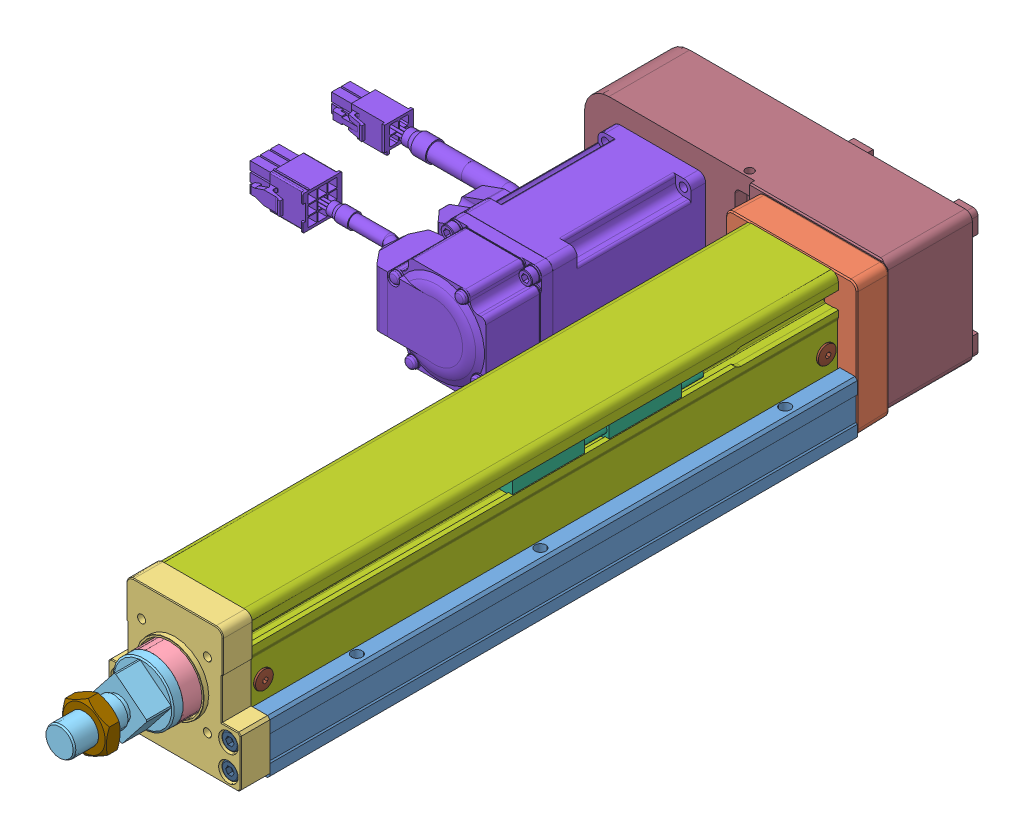
SolidWorks assembly CFY5-BL-100W, configuration Default. Lengths in mm.
Overall size (197.79 55.75 350).
25 component instances, 14 part files, 57 mates.
Components (placement in the parent):
- 底座GY5^CFY5-BL-100W-1: 底座GY5^CFY5-BL-100W [默认] at (172.2343 500.0265 205.4117) x (1 0 0) z (0 -1 0) size (54 240 25) (virtual)
- 丝杆座板GY5^CFY5-BL-100W-1: 丝杆座板GY5^CFY5-BL-100W [默认] at (172.2343 515.5765 191.9117) size (54.09 55.09 28) (virtual)
- 轴承座Y5^CFY5-BL-100W-1: 轴承座Y5^CFY5-BL-100W [Default] at (172.2343 516.7765 445.4117) size (54 54 22) (virtual)
- 推杆Y5^CFY5-BL-100W-1: 推杆Y5^CFY5-BL-100W [Default] at (172.2343 516.7765 316.4117) x (-0.030388 -0.999538 0) z (-0.999538 0.030388 0) size (25 150 25) (virtual)
- 螺纹连接头Y5^CFY5-BL-100W-1: 螺纹连接头Y5^CFY5-BL-100W [Default] at (172.2343 516.7765 470.4117) x (-0.620248 -0.784406 0) z (0 0 -1) size (25 25 47) (virtual)
- 磁性感应开关^CFY5-BL-100W-2: 磁性感应开关^CFY5-BL-100W [默认] at (191.3174 533.4018 308.9117) x (1 0 0) z (0 0 -1) size (5 6.3 39.5) (virtual)
- 上盖Y5^CFY5-BL-100W-1: 上盖Y5^CFY5-BL-100W [Default] at (153.6454 513.9765 205.4117) size (38.57 34 240) (virtual)
- 松下100W电机MSMF012L1U2^CFY5-BL-100W-1: 松下100W电机MSMF012L1U2^CFY5-BL-100W [默认] at (103.2343 516.7765 190.4117) x (0 0 -1) z (0 1 0) size (118.87 120.84 38.2) (virtual)
- 磁性感应开关^CFY5-BL-100W-3: 磁性感应开关^CFY5-BL-100W [默认] at (191.3174 533.4018 269.4117) x (1 0 0) z (0 0 -1) size (5 6.3 39.5) (virtual)
- 磁性感应开关^CFY5-BL-100W-4: 磁性感应开关^CFY5-BL-100W [默认] at (153.1454 533.4018 385.4117) x (-1 0 0) z (0 0 -1) size (5 6.3 39.5) (virtual)
- 六角薄螺母M12×1.25^CFY5-BL-100W-1: 六角薄螺母M12×1.25^CFY5-BL-100W [默认] at (172.2343 516.7765 494.4117) x (0.828588 -0.559859 0) z (0 0 1) size (20.78 18 6) (virtual)
- hexagon socket head cap screws gb-6: hexagon socket head cap screws gb [GB_FASTENER_SCREWS_HSHCS M4X12-N] at (194.2343 504.2765 456.8117) x (0 0 -1) z (1 0 0) size (16 7 7)
- hexagon socket head cap screws gb-7: hexagon socket head cap screws gb [GB_FASTENER_SCREWS_HSHCS M4X12-N] at (194.2343 493.7765 456.8117) x (0 0 -1) z (1 0 0) size (16 7 7)
- hexagon socket head cap screws gb-8: hexagon socket head cap screws gb [GB_FASTENER_SCREWS_HSHCS M4X12-N] at (150.2343 493.7765 456.8117) x (0 0 -1) z (1 0 0) size (16 7 7)
- hexagon socket head cap screws gb-9: hexagon socket head cap screws gb [GB_FASTENER_SCREWS_HSHCS M4X12-N] at (150.2343 504.2765 456.8117) x (0 0 -1) z (1 0 0) size (16 7 7)
- 内六角螺丝M3X5^CFY5-BL-100W-1: 内六角螺丝M3X5^CFY5-BL-100W [默认] at (186.1785 516.7765 210.4117) x (0 -1 0) z (0 0 1) size (7.5 6.19 7.5) (virtual)
- 内六角螺丝M3X5^CFY5-BL-100W-2: 内六角螺丝M3X5^CFY5-BL-100W [默认] at (186.1785 516.7765 440.4117) x (0 -0.21215 -0.977237) z (0 -0.977237 0.21215) size (7.5 6.19 7.5) (virtual)
- 内六角螺丝M3X5^CFY5-BL-100W-3: 内六角螺丝M3X5^CFY5-BL-100W [默认] at (158.2843 516.7765 440.4117) x (0 0.554408 0.832245) z (0 -0.832245 0.554408) size (7.5 6.19 7.5) (virtual)
- 内六角螺丝M3X5^CFY5-BL-100W-4: 内六角螺丝M3X5^CFY5-BL-100W [默认] at (158.2843 516.7765 210.4117) x (0 -0.497668 -0.867368) z (0 0.867368 -0.497668) size (7.5 6.19 7.5) (virtual)
- 304电机盖板Y5^CFY5-BL-100W-1: 304电机盖板Y5^CFY5-BL-100W [默认] at (135.4843 516.7765 157.4117) x (0 1 0) z (-1 0 0) size (51.5 1 123.5) (virtual)
- 电机板Y5-BLRM-P38^CFY5-BL-100W-1: 电机板Y5-BLRM-P38^CFY5-BL-100W [默认] at (124.0343 517.5265 205.4117) x (0 0 1) z (0 1 0) size (38 125.5 53.5) (virtual)
- hexagon socket button head screws gb-7: hexagon socket button head screws gb [GB_SOCKET_TYPE7 M3X6-N] at (79.2343 529.2765 154.7617) x (0 0 1) z (-1 0 0) size (7.65 5.7 5.7)
- hexagon socket button head screws gb-8: hexagon socket button head screws gb [GB_SOCKET_TYPE7 M3X6-N] at (79.2343 504.2765 154.7617) x (0 0 1) z (-1 0 0) size (7.65 5.7 5.7)
- hexagon socket button head screws gb-9: hexagon socket button head screws gb [GB_SOCKET_TYPE7 M3X6-N] at (192.2343 529.2765 154.7617) x (0 0 1) z (-1 0 0) size (7.65 5.7 5.7)
- hexagon socket button head screws gb-10: hexagon socket button head screws gb [GB_SOCKET_TYPE7 M3X6-N] at (192.2343 504.2765 154.7617) x (0 0 1) z (-1 0 0) size (7.65 5.7 5.7)
Mates (geometry in assembly coordinates):
- 同心129: concentric: cylinder of 推杆Y5^CFY5-BL-100W-1 through (172.2343 516.7765 466.4117) axis (0 0 -1) radius 8.5; cylinder of 螺纹连接头Y5^CFY5-BL-100W-1 through (172.2343 516.7765 457.4117) axis (0 0 1) radius 10
- 重合133: coincident: plane of 推杆Y5^CFY5-BL-100W-1 through (172.2343 516.7765 466.4117) normal (0 0 1); plane of 螺纹连接头Y5^CFY5-BL-100W-1 through (172.2343 516.7765 466.4117) normal (0 0 -1)
- 同心133: concentric: cylinder of 底座GY5^CFY5-BL-100W-1 through (194.2343 493.7765 445.4117) axis (0 0 1) radius 1.65; cylinder of 轴承座Y5^CFY5-BL-100W-1 through (194.2343 493.7765 457.4117) axis (0 0 1) radius 2.25
- 重合134: coincident: plane of 底座GY5^CFY5-BL-100W-1 through (167.2343 487.8265 445.4117) normal (0 0 1); plane of 轴承座Y5^CFY5-BL-100W-1 through (172.2343 516.7765 445.4117) normal (0 0 -1)
- 同心136: concentric: cylinder of 底座GY5^CFY5-BL-100W-1 through (150.2343 504.2765 445.4117) axis (0 0 1) radius 1.65; cylinder of 轴承座Y5^CFY5-BL-100W-1 through (150.2343 504.2765 457.4117) axis (0 0 1) radius 2.25
- 重合143: coincident: plane of 底座GY5^CFY5-BL-100W-1 through (167.2343 487.8265 445.4117) normal (0 0 1); plane of 上盖Y5^CFY5-BL-100W-1 through (158.1567 536.5769 445.4117) normal (0 0 1)
- 重合144: coincident: plane of 底座GY5^CFY5-BL-100W-1 through (190.0843 508.7765 445.4117) normal (0 1 0); plane of 上盖Y5^CFY5-BL-100W-1 through (191.1785 508.7765 445.4117) normal (0 -1 0)
- 宽度31: width: plane of 磁性感应开关^CFY5-BL-100W-2 through (186.3174 530.2518 338.4117) normal (0 -1 0); plane of 磁性感应开关^CFY5-BL-100W-2 through (186.3174 536.5518 308.9117) normal (0 1 0); plane of 上盖Y5^CFY5-BL-100W-1 through (158.1567 529.7267 445.4117) normal (0 1 0); plane of 上盖Y5^CFY5-BL-100W-1 through (154.9454 537.0769 445.4117) normal (0 -1 0)
- 重合1579: coincident: plane of 底座GY5^CFY5-BL-100W-1 through (154.3843 512.7765 445.4117) normal (-1 0 0); plane of 上盖Y5^CFY5-BL-100W-1 through (154.3843 527.7267 445.4117) normal (1 0 0)
- 重合1583: coincident: line of 磁性感应开关^CFY5-BL-100W-2 through (186.3174 530.2518 338.4117) axis (0 0 -1); plane of 磁性感应开关^CFY5-BL-100W-3 through (186.3174 533.4018 269.4117) normal (-1 0 0)
- 重合1586: coincident: plane of 磁性感应开关^CFY5-BL-100W-2 through (186.3174 530.2518 338.4117) normal (0 -1 0); plane of 磁性感应开关^CFY5-BL-100W-3 through (186.3174 530.2518 298.9117) normal (0 -1 0)
- 重合1603: coincident: plane of 磁性感应开关^CFY5-BL-100W-2 through (188.8174 533.4018 298.9117) normal (0 0 -1); plane of 磁性感应开关^CFY5-BL-100W-3 through (186.3174 536.5518 298.9117) normal (0 0 1)
- 距离9: distance = 30.5 mm: plane of 磁性感应开关^CFY5-BL-100W-4 through (158.1454 530.2518 414.9117) normal (0 0 1); plane of 轴承座Y5^CFY5-BL-100W-1 through (172.2343 516.7765 445.4117) normal (0 0 -1)
- 同心1661: concentric: cylinder of 底座GY5^CFY5-BL-100W-1 through (194.3343 506.7765 205.4117) axis (0 0 -1) radius 1.65; cylinder of 丝杆座板GY5^CFY5-BL-100W-1 through (194.3343 506.7765 192.4117) axis (0 0 -1) radius 4
- 同心1662: concentric: cylinder of 底座GY5^CFY5-BL-100W-1 through (150.1343 506.7765 205.4117) axis (0 0 -1) radius 1.65; cylinder of 丝杆座板GY5^CFY5-BL-100W-1 through (150.1343 506.7765 192.4117) axis (0 0 -1) radius 2.4
- 重合1605: coincident: plane of 底座GY5^CFY5-BL-100W-1 through (167.2343 487.8265 205.4117) normal (0 0 -1); plane of 丝杆座板GY5^CFY5-BL-100W-1 through (172.2343 515.5765 205.4117) normal (0 0 1)
- 距离11: distance = 64 mm: plane of 磁性感应开关^CFY5-BL-100W-3 through (186.3174 530.2518 269.4117) normal (0 0 -1); plane of 丝杆座板GY5^CFY5-BL-100W-1 through (172.2343 515.5765 205.4117) normal (0 0 1)
- 同心1672: concentric: cylinder of 螺纹连接头Y5^CFY5-BL-100W-1 through (172.2343 516.7765 504.4117) axis (0 0 -1) radius 6; cylinder of 六角薄螺母M12×1.25^CFY5-BL-100W-1 through (172.2343 516.7765 488.4117) axis (0 0 1) radius 5.3235
- 距离12: distance = 8 mm: plane of 螺纹连接头Y5^CFY5-BL-100W-1 through (172.2343 516.7765 480.4117) normal (0 0 1); plane of 六角薄螺母M12×1.25^CFY5-BL-100W-1 through (162.8901 512.2283 488.4117) normal (0 0 -1)
- 宽度33: width: plane of 上盖Y5^CFY5-BL-100W-1 through (189.5174 530.7267 445.4117) normal (0 1 0); plane of 上盖Y5^CFY5-BL-100W-1 through (189.5174 536.0769 445.4117) normal (0 -1 0); plane of 磁性感应开关^CFY5-BL-100W-4 through (153.1454 530.9018 414.9117) normal (0 -1 0); plane of 磁性感应开关^CFY5-BL-100W-4 through (154.9454 535.9018 414.9117) normal (0 1 0)
- 同心1673: concentric: cylinder of 轴承座Y5^CFY5-BL-100W-1 through (172.2343 516.7765 457.4117) axis (0 0 -1) radius 13.25; cylinder of 推杆Y5^CFY5-BL-100W-1 through (172.2343 516.7765 466.4117) axis (0 0 -1) radius 12.5
- 距离13: distance = 47 mm: plane of 螺纹连接头Y5^CFY5-BL-100W-1 through (172.2343 516.7765 504.4117) normal (0 0 1); plane of 轴承座Y5^CFY5-BL-100W-1 through (172.2343 516.7765 457.4117) normal (0 0 1)
- 同心1674: concentric: cylinder of 轴承座Y5^CFY5-BL-100W-1 through (194.2343 504.2765 457.4117) axis (0 0 1) radius 2.25; cylinder of hexagon socket head cap screws gb-6 through (194.2343 504.2765 440.8117) axis (0 0 1) radius 2
- 重合1618: coincident: plane of 轴承座Y5^CFY5-BL-100W-1 through (196.4843 504.2765 452.8117) normal (0 0 1); plane of hexagon socket head cap screws gb-6 through (194.2343 504.2765 452.8117) normal (0 0 -1)
- 同心1675: concentric: cylinder of 轴承座Y5^CFY5-BL-100W-1 through (194.2343 493.7765 457.4117) axis (0 0 1) radius 4; cylinder of hexagon socket head cap screws gb-7 through (194.2343 493.7765 440.8117) axis (0 0 1) radius 2
- 重合1619: coincident: plane of 轴承座Y5^CFY5-BL-100W-1 through (196.4843 493.7765 452.8117) normal (0 0 1); plane of hexagon socket head cap screws gb-7 through (194.2343 493.7765 452.8117) normal (0 0 -1)
- 同心1676: concentric: cylinder of 轴承座Y5^CFY5-BL-100W-1 through (150.2343 493.7765 457.4117) axis (0 0 1) radius 2.25; cylinder of hexagon socket head cap screws gb-8 through (150.2343 493.7765 440.8117) axis (0 0 1) radius 2
- 重合1620: coincident: plane of 轴承座Y5^CFY5-BL-100W-1 through (152.4843 493.7765 452.8117) normal (0 0 1); plane of hexagon socket head cap screws gb-8 through (150.2343 493.7765 452.8117) normal (0 0 -1)
- 同心1677: concentric: cylinder of 轴承座Y5^CFY5-BL-100W-1 through (150.2343 504.2765 457.4117) axis (0 0 1) radius 2.25; cylinder of hexagon socket head cap screws gb-9 through (150.2343 504.2765 440.8117) axis (0 0 1) radius 2
- 重合1621: coincident: plane of 轴承座Y5^CFY5-BL-100W-1 through (152.4843 504.2765 452.8117) normal (0 0 1); plane of hexagon socket head cap screws gb-9 through (150.2343 504.2765 452.8117) normal (0 0 -1)
- 同心1678: concentric: cylinder of 丝杆座板GY5^CFY5-BL-100W-1 through (189.9843 516.7765 210.4117) axis (1 0 0) radius 1.25; cylinder of 内六角螺丝M3X5^CFY5-BL-100W-1 through (186.1785 516.7765 210.4117) axis (-1 0 0) radius 1.5
- 重合1622: coincident: plane of 上盖Y5^CFY5-BL-100W-1 through (191.1785 526.1852 445.4117) normal (1 0 0); circle of 内六角螺丝M3X5^CFY5-BL-100W-1
- 同心1679: concentric: cylinder of 上盖Y5^CFY5-BL-100W-1 through (153.2843 516.7765 440.4117) axis (-1 0 0) radius 1.75; cylinder of 内六角螺丝M3X5^CFY5-BL-100W-2 through (186.1785 516.7765 440.4117) axis (-1 0 0) radius 1.5
- 重合1623: coincident: plane of 上盖Y5^CFY5-BL-100W-1 through (191.1785 526.1852 445.4117) normal (1 0 0); plane of 内六角螺丝M3X5^CFY5-BL-100W-2 through (191.1785 516.7765 440.4117) normal (-1 0 0)
- 重合1624: coincident: plane of 上盖Y5^CFY5-BL-100W-1 through (153.2843 526.1852 445.4117) normal (-1 0 0); plane of 内六角螺丝M3X5^CFY5-BL-100W-3 through (153.2843 516.7765 440.4117) normal (1 0 0)
- 同心1680: concentric: cylinder of 上盖Y5^CFY5-BL-100W-1 through (153.2843 516.7765 440.4117) axis (-1 0 0) radius 1.75; cylinder of 内六角螺丝M3X5^CFY5-BL-100W-3 through (158.2843 516.7765 440.4117) axis (1 0 0) radius 1.5
- 同心1681: concentric: cylinder of 上盖Y5^CFY5-BL-100W-1 through (153.2843 516.7765 210.4117) axis (-1 0 0) radius 1.75; cylinder of 内六角螺丝M3X5^CFY5-BL-100W-4 through (158.2843 516.7765 210.4117) axis (1 0 0) radius 1.5
- 重合1625: coincident: plane of 上盖Y5^CFY5-BL-100W-1 through (153.2843 526.1852 445.4117) normal (-1 0 0); plane of 内六角螺丝M3X5^CFY5-BL-100W-4 through (153.2843 516.7765 210.4117) normal (1 0 0)
- 同心1691: concentric: cylinder of 304电机盖板Y5^CFY5-BL-100W-1 through (79.2343 529.2765 156.4117) axis (0 0 -1) radius 1.7; cylinder of hexagon socket button head screws gb-7 through (79.2343 529.2765 162.4117) axis (0 0 -1) radius 1.5
- 重合1631: coincident: plane of 304电机盖板Y5^CFY5-BL-100W-1 through (156.2343 541.5265 156.4117) normal (0 0 -1); plane of hexagon socket button head screws gb-7 through (79.2343 529.2765 156.4117) normal (0 0 1)
- 同心1692: concentric: cylinder of 304电机盖板Y5^CFY5-BL-100W-1 through (79.2343 504.2765 156.4117) axis (0 0 -1) radius 1.7; cylinder of hexagon socket button head screws gb-8 through (79.2343 504.2765 162.4117) axis (0 0 -1) radius 1.5
- 重合1632: coincident: plane of 304电机盖板Y5^CFY5-BL-100W-1 through (156.2343 541.5265 156.4117) normal (0 0 -1); plane of hexagon socket button head screws gb-8 through (79.2343 504.2765 156.4117) normal (0 0 1)
- 同心1693: concentric: cylinder of 304电机盖板Y5^CFY5-BL-100W-1 through (192.2343 529.2765 156.4117) axis (0 0 -1) radius 1.7; cylinder of hexagon socket button head screws gb-9 through (192.2343 529.2765 162.4117) axis (0 0 -1) radius 1.5
- 重合1633: coincident: plane of 304电机盖板Y5^CFY5-BL-100W-1 through (156.2343 541.5265 156.4117) normal (0 0 -1); plane of hexagon socket button head screws gb-9 through (192.2343 529.2765 156.4117) normal (0 0 1)
- 同心1694: concentric: cylinder of 304电机盖板Y5^CFY5-BL-100W-1 through (192.2343 504.2765 156.4117) axis (0 0 -1) radius 1.7; cylinder of hexagon socket button head screws gb-10 through (192.2343 504.2765 162.4117) axis (0 0 -1) radius 1.5
- 重合1634: coincident: plane of 304电机盖板Y5^CFY5-BL-100W-1 through (156.2343 541.5265 156.4117) normal (0 0 -1); plane of hexagon socket button head screws gb-10 through (192.2343 504.2765 156.4117) normal (0 0 1)
- 同心1695: concentric: cylinder of 丝杆座板GY5^CFY5-BL-100W-1 through (172.2343 516.7765 192.4117) axis (0 0 -1) radius 16; cylinder of 电机板Y5-BLRM-P38^CFY5-BL-100W-1 through (172.2343 516.7765 192.4117) axis (0 0 -1) radius 16
- 重合1635: coincident: plane of 丝杆座板GY5^CFY5-BL-100W-1 through (172.2343 516.7765 192.4117) normal (0 0 -1); plane of 电机板Y5-BLRM-P38^CFY5-BL-100W-1 through (124.0343 517.5265 192.4117) normal (0 0 1)
- 同心1696: concentric: cylinder of 丝杆座板GY5^CFY5-BL-100W-1 through (172.2343 537.2765 192.4117) axis (0 0 -1) radius 1.65; cylinder of 电机板Y5-BLRM-P38^CFY5-BL-100W-1 through (172.2343 537.2765 157.4117) axis (0 0 -1) radius 2.25
- 重合1636: coincident: plane of 304电机盖板Y5^CFY5-BL-100W-1 through (156.2343 541.5265 157.4117) normal (0 0 1); plane of 电机板Y5-BLRM-P38^CFY5-BL-100W-1 through (124.0343 517.5265 157.4117) normal (0 0 -1)
- 同心1697: concentric: cylinder of hexagon socket button head screws gb-9 through (192.2343 529.2765 162.4117) axis (0 0 -1) radius 1.5; cylinder of 电机板Y5-BLRM-P38^CFY5-BL-100W-1 through (192.2343 529.2765 157.4117) axis (0 0 -1) radius 1.25
- 同心1698: concentric: cylinder of hexagon socket button head screws gb-8 through (79.2343 504.2765 162.4117) axis (0 0 -1) radius 1.5; cylinder of 电机板Y5-BLRM-P38^CFY5-BL-100W-1 through (79.2343 504.2765 157.4117) axis (0 0 -1) radius 1.25
- 同心1699: concentric: cylinder of 松下100W电机MSMF012L1U2^CFY5-BL-100W-1 through (87.3244 532.6864 196.4117) axis (0 0 1) radius 1.7; cylinder of 电机板Y5-BLRM-P38^CFY5-BL-100W-1 through (87.3244 532.6864 192.4117) axis (0 0 1) radius 1.25
- 同心1700: concentric: cylinder of 松下100W电机MSMF012L1U2^CFY5-BL-100W-1 through (103.2343 516.7765 165.4117) axis (0 0 1) radius 4; cylinder of 电机板Y5-BLRM-P38^CFY5-BL-100W-1 through (103.2343 516.7765 179.4117) axis (0 0 1) radius 15
- 重合1637: coincident: plane of 松下100W电机MSMF012L1U2^CFY5-BL-100W-1 through (87.2343 532.7765 190.4117) normal (0 0 -1); plane of 电机板Y5-BLRM-P38^CFY5-BL-100W-1 through (124.0343 517.5265 190.4117) normal (0 0 1)
- 重合1638: coincident: plane of 上盖Y5^CFY5-BL-100W-1 through (154.9454 536.0769 445.4117) normal (1 0 0); plane of 磁性感应开关^CFY5-BL-100W-4 through (154.9454 530.9018 414.9117) normal (-1 0 0)
- 重合1639: coincident: plane of 上盖Y5^CFY5-BL-100W-1 through (189.5174 529.7267 445.4117) normal (-1 0 0); plane of 磁性感应开关^CFY5-BL-100W-3 through (189.5174 530.2518 298.9117) normal (1 0 0)
